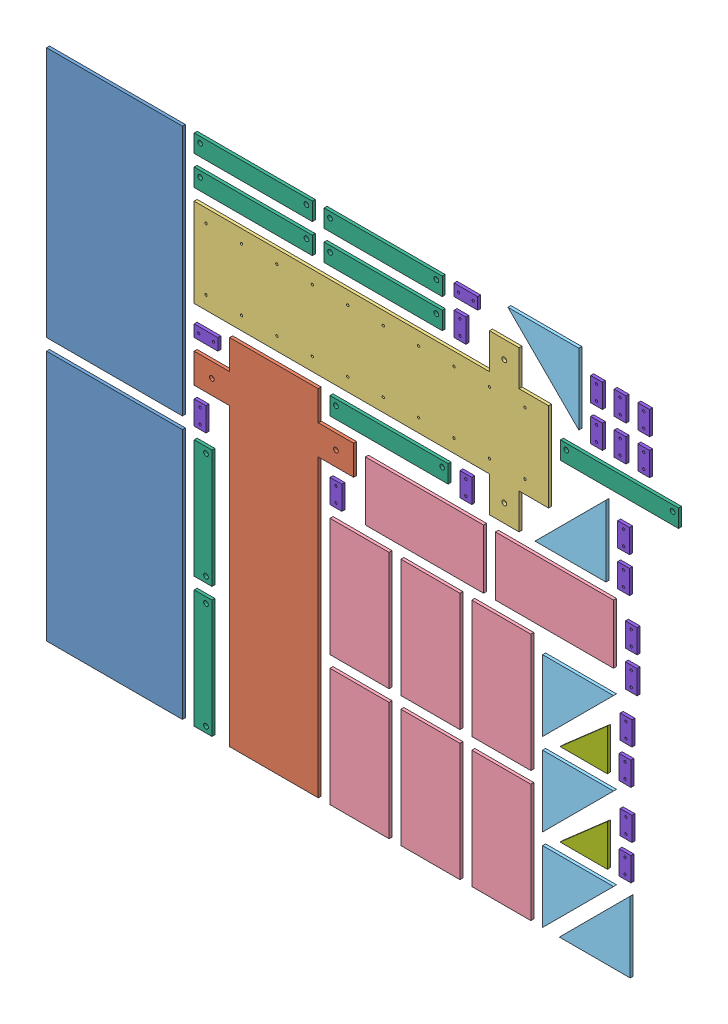
SolidWorks assembly Nest(5mm), configuration Layout1[Steel_5mm_Qnty1]. Lengths in mm.
Overall size (1800 900 5).
48 component instances, 8 part files, 0 mates.
Components (placement in the parent):
- Z_Plate_2-1: Z_Plate_2 [Default] at (125 227.5 0) x (1 0 0) z (0 0 -1) size (230 425 5)
- Z_Plate_2-2: Z_Plate_2 [Default] at (125 672.5 0) x (1 0 0) z (0 0 -1) size (230 425 5)
- Z_Plate_1-1: Z_Plate_1 [Default] at (395 310 0) x (1 0 0) z (0 0 -1) size (270 600 5)
- Z_Plate_1 - Copy-1: Z_Plate_1 - Copy [Default] at (560 705 0) x (0 -1 0) z (0 0 -1) size (270 600 5)
- C Covering 1-1: C Covering 1 [Default] at (540 110 0) x (0 -1 0) z (0 0 -1) size (200 100 5)
- C Covering 1-2: C Covering 1 [Default] at (540 330 0) x (0 -1 0) z (0 0 -1) size (200 100 5)
- C Covering 1-3: C Covering 1 [Default] at (650 500 0) x (1 0 0) z (0 0 -1) size (200 100 5)
- C Covering 1-4: C Covering 1 [Default] at (660 110 0) x (0 -1 0) z (0 0 -1) size (200 100 5)
- C Covering 1-5: C Covering 1 [Default] at (660 330 0) x (0 -1 0) z (0 0 -1) size (200 100 5)
- C Covering 1-6: C Covering 1 [Default] at (780 110 0) x (0 -1 0) z (0 0 -1) size (200 100 5)
- C Covering 1-7: C Covering 1 [Default] at (780 330 0) x (0 -1 0) z (0 0 -1) size (200 100 5)
- C Covering 1-8: C Covering 1 [Default] at (870 500 0) x (1 0 0) z (0 0 -1) size (200 100 5)
- Motor Extension Rib-1: Motor Extension Rib [Default] at (911.2132 890 0) x (0 -1 0) z (0 0 -1) size (120 120 5)
- Motor Extension Rib-2: Motor Extension Rib [Default] at (850 130 0) x (1 0 0) z (0 0 -1) size (120 120 5)
- Motor Extension Rib-3: Motor Extension Rib [Default] at (850 270 0) x (1 0 0) z (0 0 -1) size (120 120 5)
- Motor Extension Rib-4: Motor Extension Rib [Default] at (850 410 0) x (1 0 0) z (0 0 -1) size (120 120 5)
- Motor Extension Rib-5: Motor Extension Rib [Default] at (957.0711 570 0) x (-1 0 0) z (0 0 -1) size (120 120 5)
- Motor Extension Rib-6: Motor Extension Rib [Default] at (998.2843 10 0) x (-1 0 0) z (0 0 -1) size (120 120 5)
- C Covering 2-1: C Covering 2 [Default] at (275 110 0) x (0 -1 0) z (0 0 -1) size (200 30 5)
- C Covering 2-2: C Covering 2 [Default] at (275 330 0) x (0 -1 0) z (0 0 -1) size (200 30 5)
- C Covering 2-3: C Covering 2 [Default] at (360 815 0) x (1 0 0) z (0 0 -1) size (200 30 5)
- C Covering 2-4: C Covering 2 [Default] at (360 865 0) x (1 0 0) z (0 0 -1) size (200 30 5)
- C Covering 2-5: C Covering 2 [Default] at (580 815 0) x (1 0 0) z (0 0 -1) size (200 30 5)
- C Covering 2-6: C Covering 2 [Default] at (580 865 0) x (1 0 0) z (0 0 -1) size (200 30 5)
- C Covering 2-7: C Covering 2 [Default] at (590 595 0) x (1 0 0) z (0 0 -1) size (200 30 5)
- C Covering 2-8: C Covering 2 [Default] at (980 725 0) x (1 0 0) z (0 0 -1) size (200 30 5)
- Rib-1: Rib [Default] at (959.5205 150 0) x (0 0 -1) z (1 0 0) size (5 70 80)
- Rib-2: Rib [Default] at (959.5205 290 0) x (0 0 -1) z (1 0 0) size (5 70 80)
- Bracket_Plate-1: Bracket_Plate [Default] at (270 470 0) x (0 -1 0) z (1 0 0) size (40 5 20)
- Bracket_Plate-2: Bracket_Plate [Default] at (280 590 0) x (1 0 0) z (0 1 0) size (40 5 20)
- Bracket_Plate-3: Bracket_Plate [Default] at (500 470 0) x (0 -1 0) z (1 0 0) size (40 5 20)
- Bracket_Plate-4: Bracket_Plate [Default] at (710 820 0) x (0 -1 0) z (1 0 0) size (40 5 20)
- Bracket_Plate-5: Bracket_Plate [Default] at (720 590 0) x (0 -1 0) z (1 0 0) size (40 5 20)
- Bracket_Plate-6: Bracket_Plate [Default] at (720 870 0) x (1 0 0) z (0 1 0) size (40 5 20)
- Bracket_Plate-7: Bracket_Plate [Default] at (941.2132 780 0) x (0 -1 0) z (1 0 0) size (40 5 20)
- Bracket_Plate-8: Bracket_Plate [Default] at (941.2132 840 0) x (0 -1 0) z (1 0 0) size (40 5 20)
- Bracket_Plate-9: Bracket_Plate [Default] at (981.2132 780 0) x (0 -1 0) z (1 0 0) size (40 5 20)
- Bracket_Plate-10: Bracket_Plate [Default] at (981.2132 840 0) x (0 -1 0) z (1 0 0) size (40 5 20)
- Bracket_Plate-11: Bracket_Plate [Default] at (987.0711 590 0) x (0 -1 0) z (1 0 0) size (40 5 20)
- Bracket_Plate-12: Bracket_Plate [Default] at (987.0711 650 0) x (0 -1 0) z (1 0 0) size (40 5 20)
- Bracket_Plate-13: Bracket_Plate [Default] at (989.5205 170 0) x (0 -1 0) z (1 0 0) size (40 5 20)
- Bracket_Plate-14: Bracket_Plate [Default] at (991.2132 230 0) x (0 -1 0) z (1 0 0) size (40 5 20)
- Bracket_Plate-15: Bracket_Plate [Default] at (989.5205 310 0) x (0 -1 0) z (1 0 0) size (40 5 20)
- Bracket_Plate-16: Bracket_Plate [Default] at (991.2132 370 0) x (0 -1 0) z (1 0 0) size (40 5 20)
- Bracket_Plate-17: Bracket_Plate [Default] at (1000 449.5615 0) x (0 -1 0) z (1 0 0) size (40 5 20)
- Bracket_Plate-18: Bracket_Plate [Default] at (1000 509.5615 0) x (0 -1 0) z (1 0 0) size (40 5 20)
- Bracket_Plate-19: Bracket_Plate [Default] at (1021.2132 780 0) x (0 -1 0) z (1 0 0) size (40 5 20)
- Bracket_Plate-20: Bracket_Plate [Default] at (1021.2132 840 0) x (0 -1 0) z (1 0 0) size (40 5 20)
